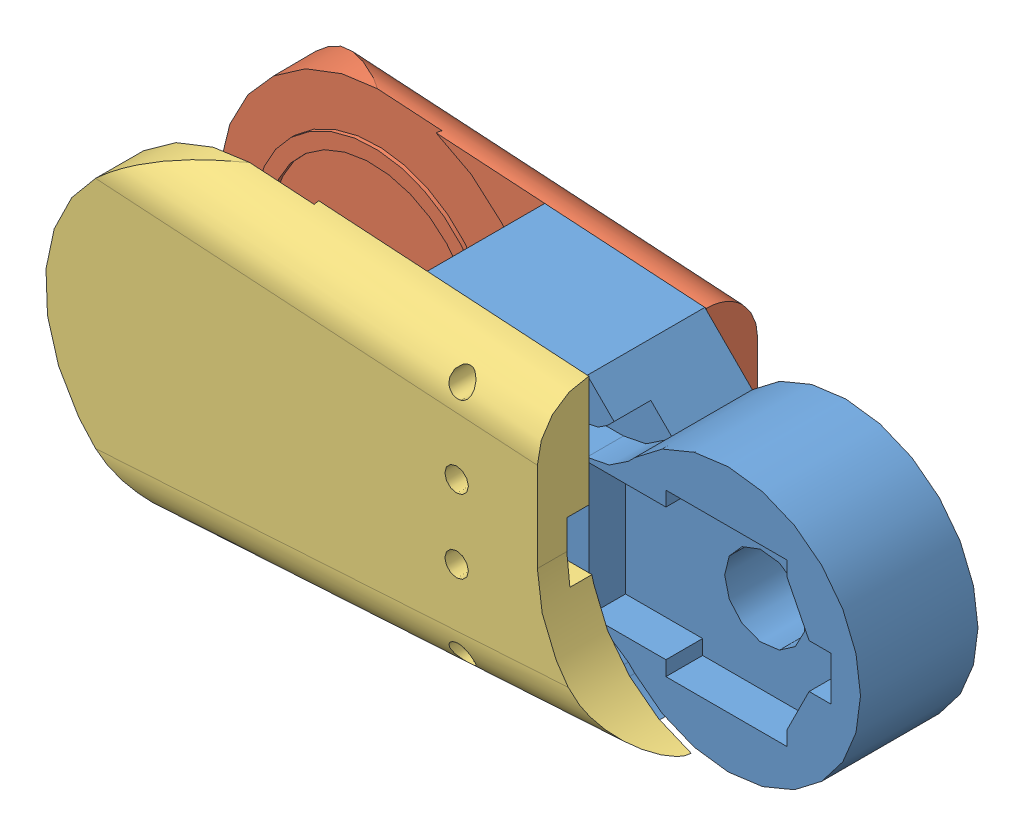
SolidWorks assembly thumbM-assembly, configuration Default. Lengths in mm.
Overall size (52 22 16.39).
3 component instances, 3 part files, 6 mates.
Components (placement in the parent):
- thumbM-middle-2: thumbM-middle [Default] at (-25.772 17.4488 -36.6574) size (36.9 21.02 8)
- thumbM-left-2: thumbM-left [Default] at (6.228 17.4488 -40.1574) size (40.91 22 6.45)
- thumbM-right-2: thumbM-right [Default] at (6.228 17.4488 -28.6574) size (40.87 22 7.09)
Mates (geometry in assembly coordinates):
- Concentric1: concentric aligned: cylinder of thumbM-middle-2 through (-8.772 19.9488 -28.6574) axis (0 0 -1) radius 0.8; cylinder of thumbM-left-2 through (-8.772 19.9488 -34.4074) axis (0 0 -1) radius 0.8
- Concentric2: concentric aligned: cylinder of thumbM-middle-2 through (-8.772 14.9488 -28.6574) axis (0 0 -1) radius 0.8; cylinder of thumbM-left-2 through (-8.772 14.9488 -34.4074) axis (0 0 -1) radius 0.8
- Coincident1: coincident anti-aligned: plane of thumbM-middle-2 through (-25.772 17.4488 -36.6574) normal (0 0 -1); plane of thumbM-left-2 through (6.228 17.4488 -36.6574) normal (0 0 1)
- Concentric3: concentric aligned: cylinder of thumbM-middle-2 through (-8.772 19.9488 -28.6574) axis (0 0 -1) radius 0.8; cylinder of thumbM-right-2 through (-8.772 19.9488 -25.1574) axis (0 0 -1) radius 0.8
- Concentric4: concentric aligned: cylinder of thumbM-middle-2 through (-8.772 14.9488 -28.6574) axis (0 0 -1) radius 0.8; cylinder of thumbM-right-2 through (-8.772 14.9488 -25.1574) axis (0 0 -1) radius 0.8
- Coincident2: coincident anti-aligned: plane of thumbM-middle-2 through (-25.772 17.4488 -28.6574) normal (0 0 1); plane of thumbM-right-2 through (6.228 17.4488 -28.6574) normal (0 0 -1)
